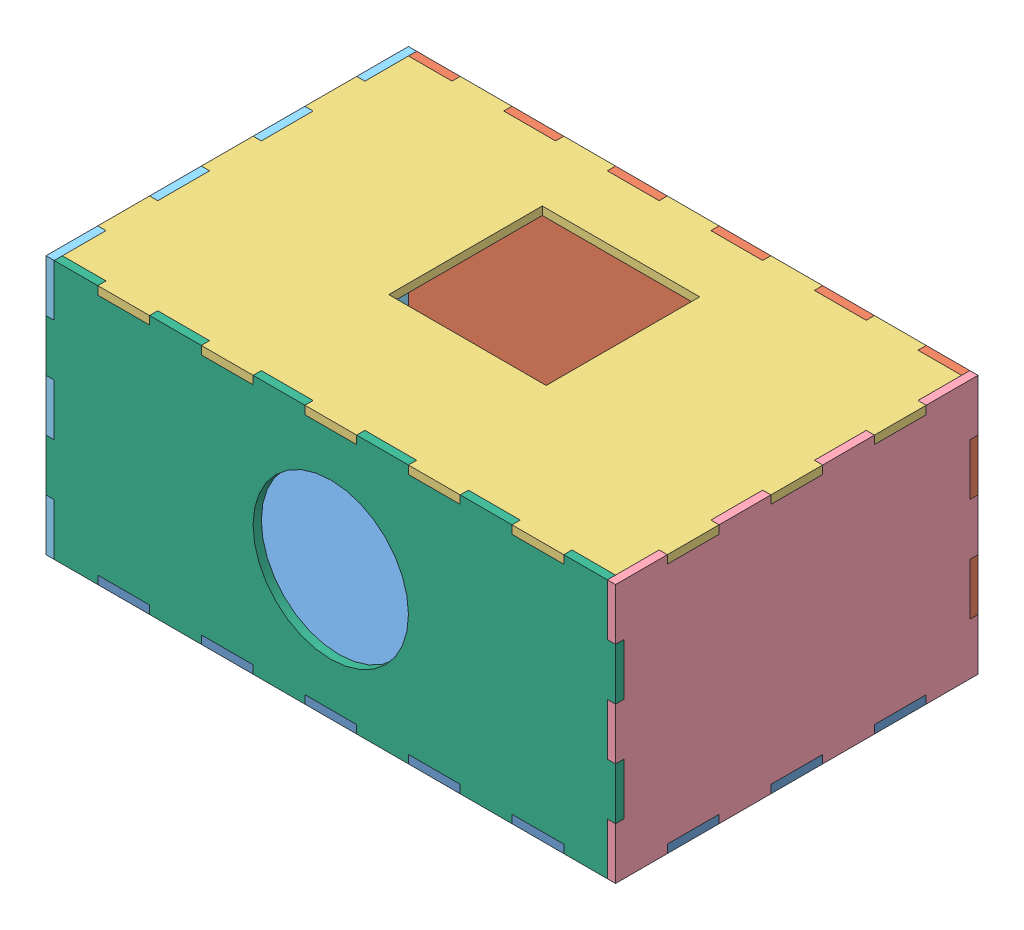
SolidWorks assembly BoxAssem, configuration Default. Lengths in mm.
Overall size (220 100 140).
6 component instances, 6 part files, 16 mates.
Components (placement in the parent):
- Back-1: Back [Default] at (78.713 94.2058 -482.3599) size (220 3.17 140)
- Bottom-1: Bottom [Default] at (78.713 141.0309 115.742) x (1 0 0) z (0 0 -1) size (220 100 3.17)
- Front-1: Front [Default] at (78.713 187.8558 -482.3599) size (220 3.17 140)
- Left-1: Left [Default] at (185.538 141.0308 -482.3599) size (3.17 100 140)
- Right-1: Right [Default] at (-28.112 141.0308 -482.3599) size (3.17 100 140)
- Top-1: Top [Default] at (78.713 141.0308 -479.9705) size (220 100 3.18)
Mates (geometry in assembly coordinates):
- Coincident1: coincident: plane of Bottom-1 through (-28.112 171.0308 189.1654) normal (-1 0 0); plane of Right-1 through (-28.112 141.0308 -408.9365) normal (1 0 0)
- Coincident2: coincident: plane of Bottom-1 through (-31.287 171.0308 189.1654) normal (0 1 0); plane of Right-1 through (-28.112 171.0308 189.1654) normal (0 -1 0)
- Coincident3: coincident: plane of Bottom-1 through (78.713 141.0309 189.1654) normal (0 0 -1); plane of Right-1 through (-31.287 191.0308 189.1654) normal (0 0 -1)
- Coincident4: coincident: plane of Bottom-1 through (28.713 187.8558 189.1654) normal (0 1 0); plane of Front-1 through (78.713 187.8558 -408.9365) normal (0 -1 0)
- Coincident5: coincident: plane of Bottom-1 through (-11.287 191.0308 189.1654) normal (1 0 0); plane of Front-1 through (-11.287 187.8558 189.1654) normal (-1 0 0)
- Coincident6: coincident: plane of Bottom-1 through (78.713 141.0309 189.1654) normal (0 0 -1); plane of Front-1 through (188.713 191.0308 189.1654) normal (0 0 -1)
- Coincident8: coincident: plane of Bottom-1 through (188.713 151.0308 189.1654) normal (0 -1 0); plane of Left-1 through (185.538 151.0308 189.1654) normal (0 1 0)
- Coincident9: coincident: plane of Bottom-1 through (78.713 141.0309 189.1654) normal (0 0 -1); plane of Left-1 through (188.713 91.0308 189.1654) normal (0 0 -1)
- Parallel1: parallel: line of Bottom-1 through (185.538 111.0308 192.3404) axis (0 -1 0); plane of Left-1 through (185.538 141.0308 -408.9365) normal (-1 0 0)
- Coincident11: coincident: plane of Bottom-1 through (185.538 91.0308 115.742) normal (1 0 0); plane of Left-1 through (185.538 141.0308 -482.3599) normal (-1 0 0)
- Coincident12: coincident: plane of Back-1 through (78.713 94.2058 -482.3599) normal (0 1 0); plane of Bottom-1 through (148.713 94.2058 115.742) normal (0 -1 0)
- Coincident13: coincident: plane of Back-1 through (-11.287 94.2058 115.742) normal (-1 0 0); plane of Bottom-1 through (-11.287 91.0308 115.742) normal (1 0 0)
- Coincident14: coincident: plane of Back-1 through (-31.287 91.0308 115.742) normal (0 0 -1); plane of Bottom-1 through (78.713 141.0309 115.742) normal (0 0 -1)
- Coincident15: coincident: plane of Back-1 through (128.713 94.2058 252.567) normal (0 0 1); plane of Top-1 through (78.713 141.0308 252.567) normal (0 0 -1)
- Coincident16: coincident: plane of Right-1 through (-28.112 111.0308 255.742) normal (0 1 0); plane of Top-1 through (-31.287 111.0308 252.567) normal (0 -1 0)
- Coincident17: coincident: plane of Right-1 through (-31.287 141.0308 -482.3599) normal (-1 0 0); plane of Top-1 through (-31.287 91.0308 255.742) normal (-1 0 0)
